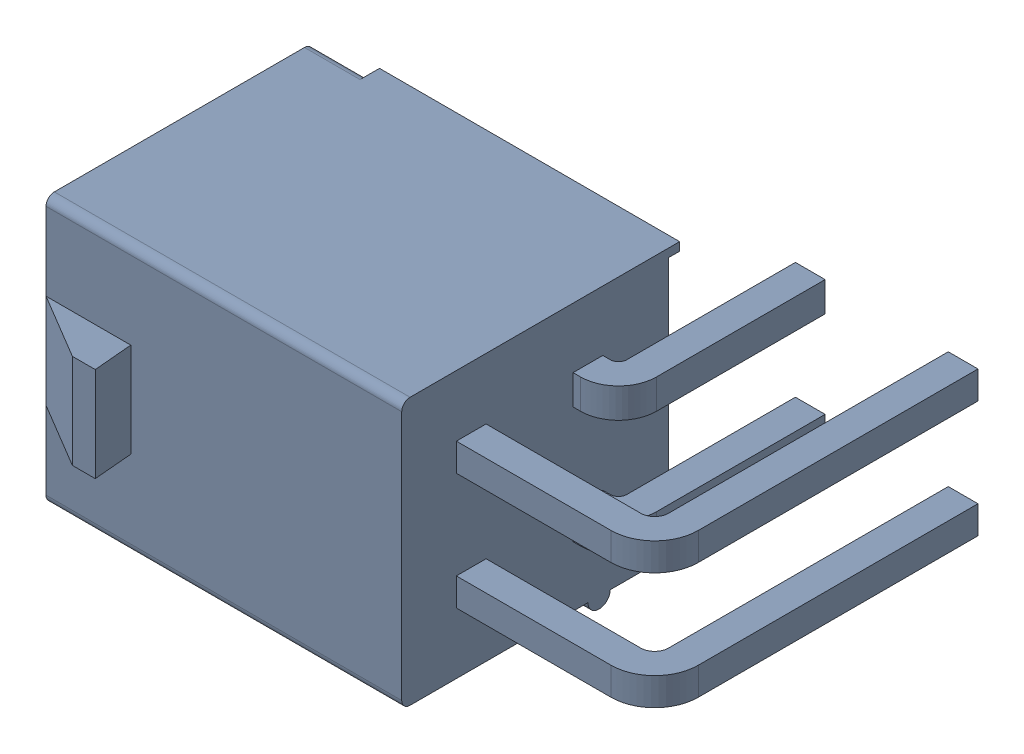
SolidWorks assembly POWER, configuration Default. Lengths in mm.
Overall size (19.94 10 15).
2 component instances, 1 part files, 0 mates.
Components (placement in the parent):
- 039300040-1: 039300040 [Default] at (114.9497 138.4306 0.0127) x (0 -1 0) z (-1 0 0) size (10 15 19.94)
  - Open CASCADE STEP translator 6.2 18.5.1.1-1: Open CASCADE STEP translator 6.2 18.5.1.1 [Default] at origin size (10 15 19.94)
